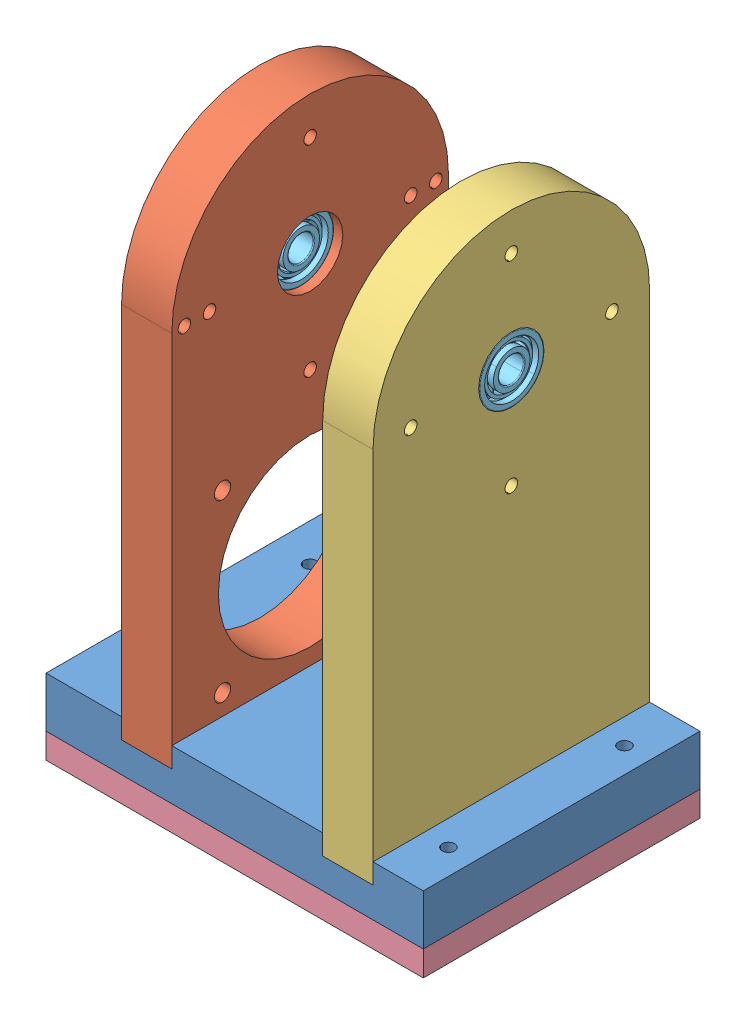
SolidWorks assembly Assembly shoulder joint, configuration Default. Lengths in mm.
Overall size (150 227 110).
6 component instances, 5 part files, 10 mates.
Components (placement in the parent):
- J2 base plate-1: J2 base plate [Default] at (48.0076 98.1183 105.8715) size (150 20 110)
- J2 Left plate-1: J2 Left plate [Default] at (3.5936 110.1183 158.62) x (0 0 -1) z (1 0 0) size (110 205 20)
- J2 right plate-2: J2 right plate [Default] at (103.5936 110.1183 163.1229) x (0 0 1) z (-1 0 0) size (110 205 20)
- J2 bottom plate-1: J2 bottom plate [Default] at (98.917 98.1183 161.6924) x (1 0 0) z (0 -1 0) size (150 110 10)
- AST_Bearings_6000-1: AST_Bearings_6000 [Default] at (16.0741 260.1183 160.8715) x (1 0 0) z (0 0.59504 0.803696) size (8 26 26.01)
- AST_Bearings_6000-2: AST_Bearings_6000 [Default] at (99.745 260.1183 160.8715) x (1 0 0) z (0 0.830749 -0.556648) size (8 26 26.01)
Mates (geometry in assembly coordinates):
- Coincident1: coincident aligned: line of J2 base plate-1 through (23.5936 110.1183 215.8715) axis (0 0 -1); line of J2 Left plate-1 through (23.5936 110.1183 215.8715) axis (0 0 -1)
- Coincident2: coincident anti-aligned: plane of J2 base plate-1 through (23.5936 110.1183 215.8715) normal (0 1 0); plane of J2 Left plate-1 through (23.5936 110.1183 215.8715) normal (0 -1 0)
- Coincident3: coincident: point of J2 base plate-1; point of J2 Left plate-1
- Coincident4: coincident anti-aligned: line of J2 base plate-1 through (103.5936 110.1183 215.8715) axis (0 0 -1); line of J2 right plate-2 through (103.5936 110.1183 105.8715) axis (0 0 1)
- Coincident5: coincident anti-aligned: plane of J2 base plate-1 through (103.5936 110.1183 215.8715) normal (0 1 0); plane of J2 right plate-2 through (83.5936 110.1183 105.8715) normal (0 -1 0)
- Coincident6: coincident: point of J2 base plate-1; point of J2 right plate-2
- Coincident7: coincident anti-aligned: plane of J2 base plate-1 through (-26.4064 98.1183 215.8715) normal (0 -1 0); plane of J2 bottom plate-1 through (98.917 98.1183 161.6924) normal (0 1 0)
- Coincident8: coincident: point of J2 base plate-1; point of J2 bottom plate-1
- Concentric1: concentric aligned: circle of J2 Left plate-1; circle of AST_Bearings_6000-1
- Concentric2: concentric anti-aligned: circle of J2 right plate-2; circle of AST_Bearings_6000-2
